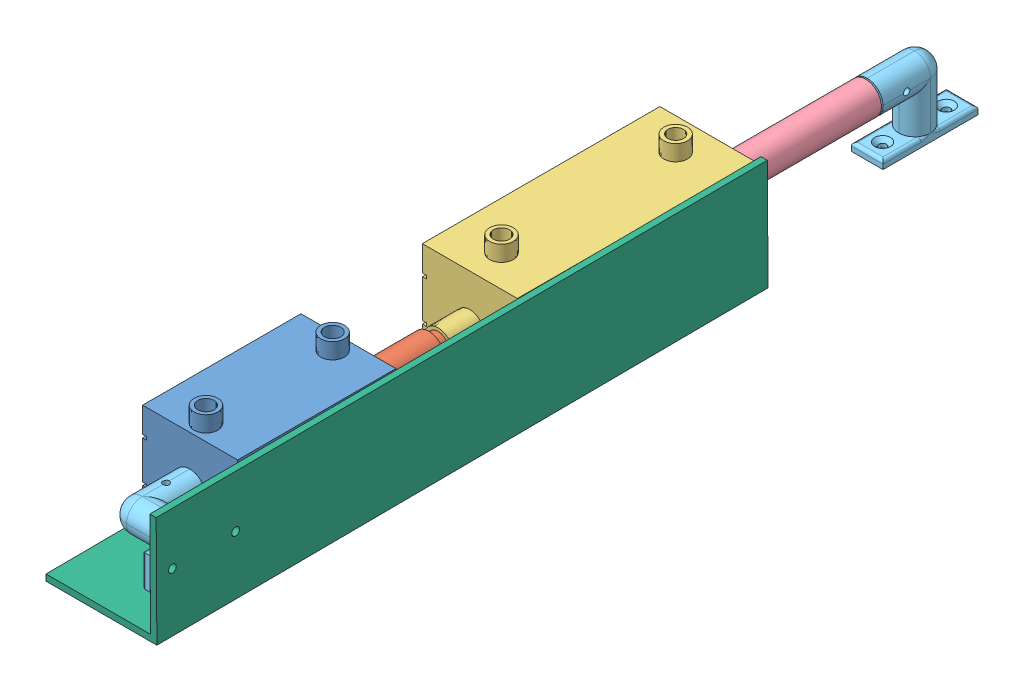
SolidWorks assembly Assem1, configuration Default. Lengths in mm.
Overall size (35 38.53 273.9).
7 component instances, 6 part files, 15 mates.
Components (placement in the parent):
- cyl1-1: cyl1 [Default] at (-32.705 23.0181 67.5747) size (30 35 60)
- cyl1shaft-1: cyl1shaft [Default] at (-17.705 23.0181 7.1747) size (10 10 35.4)
- piston2cylinder-1: piston2cylinder [Default] at (-32.705 23.0181 -33.2517) size (30 35 85)
- cyl2shaft-1: cyl2shaft [Default] at (-17.705 23.0181 -130.7517) x (-1 0 0) z (0 0 1) size (10 10 60.8)
- pistonbeltconnector-1: pistonbeltconnector [Default] at (-22.705 8.0181 -141.2203) size (10 22.49 30)
- pistonbeltconnector-2: pistonbeltconnector [Default] at (-2.8194 28.0181 112.5747) x (0 -1 0) z (0 0 -1) size (10 22.49 30)
- Lbracket-1: Lbracket [Default] at (-33.3272 4.4866 122.456) x (1 0 0) z (0 -0.00639 0.99998) size (35 35 193)
Mates (geometry in assembly coordinates):
- Concentric1: concentric aligned: cylinder of cyl1-1 through (-17.705 23.0181 82.5747) axis (0 0 -1) radius 5; cylinder of cyl1shaft-1 through (-17.705 23.0181 42.5747) axis (0 0 -1) radius 5
- LimitDistance1: limit distance = 25.4 mm aligned: plane of cyl1shaft-1 through (-17.705 23.0181 17.1747) normal (0 0 -1); plane of cyl1-1 through (-2.705 8.0181 42.5747) normal (0 0 -1)
- Concentric2: concentric aligned: cylinder of cyl1shaft-1 through (-17.705 23.0181 17.1747) axis (0 0 -1) radius 3.5; cylinder of piston2cylinder-1 through (-17.705 23.0181 14.2483) axis (0 0 -1) radius 3.5
- Concentric5: concentric anti-aligned: cylinder of cyl1shaft-1 through (-22.705 23.0181 9.2061) axis (1 0 0) radius 1; cylinder of piston2cylinder-1 through (-2.705 23.0181 9.2061) axis (-1 0 0) radius 1
- Parallel1: parallel aligned: plane of cyl1-1 through (-2.705 38.0181 92.5747) normal (0 1 0); plane of piston2cylinder-1 through (-2.705 38.0181 4.2483) normal (0 1 0)
- Concentric6: concentric aligned: cylinder of piston2cylinder-1 through (-17.705 23.0181 -10.7517) axis (0 0 -1) radius 5; cylinder of cyl2shaft-1 through (-17.705 23.0181 -69.9517) axis (0 0 -1) radius 5
- LimitDistance2: limit distance = 50 mm aligned: plane of cyl2shaft-1 through (-17.705 23.0181 -120.7517) normal (0 0 -1); plane of piston2cylinder-1 through (-2.705 8.0181 -70.7517) normal (0 0 -1)
- Concentric7: concentric anti-aligned: cylinder of cyl2shaft-1 through (-17.705 23.0181 -120.7517) axis (0 0 -1) radius 3.5; cylinder of pistonbeltconnector-1 through (-17.705 23.0181 -131.2203) axis (0 0 1) radius 3.5
- Concentric8: concentric aligned: cylinder of cyl2shaft-1 through (-12.705 23.0181 -128.7203) axis (-1 0 0) radius 1; cylinder of pistonbeltconnector-1 through (-12.705 23.0181 -128.7203) axis (-1 0 0) radius 1
- Parallel2: parallel aligned: plane of piston2cylinder-1 through (-2.705 8.0181 4.2483) normal (0 -1 0); plane of pistonbeltconnector-1 through (-12.705 5.5259 -121.2203) normal (0 -1 0)
- Concentric9: concentric aligned: cylinder of cyl1-1 through (-17.8194 23.0181 102.5747) axis (0 0 -1) radius 3.5; cylinder of pistonbeltconnector-2 through (-17.8194 23.0181 102.5747) axis (0 0 -1) radius 3.5
- Concentric13: concentric aligned: cylinder of cyl1-1 through (-17.8194 8.0181 100.0747) axis (0 1 0) radius 1; cylinder of pistonbeltconnector-2 through (-17.8194 18.0181 100.0747) axis (0 1 0) radius 1
- Concentric14: concentric aligned: cylinder of pistonbeltconnector-2 through (-10.3272 23.0181 117.5747) axis (1 0 0) radius 1.25; cylinder of Lbracket-1 through (-33.3272 23.0181 117.5743) axis (1 0 0) radius 1.25
- Concentric15: concentric aligned: cylinder of pistonbeltconnector-2 through (-10.3272 23.1459 97.5747) axis (1 0 0) radius 1.25; cylinder of Lbracket-1 through (-33.3272 23.1459 97.5747) axis (1 0 0) radius 1.25
- Coincident1: coincident anti-aligned: plane of pistonbeltconnector-2 through (-0.3272 18.0181 92.5747) normal (1 0 0); plane of Lbracket-1 through (-0.3272 40.7192 -70.3164) normal (-1 0 0)
